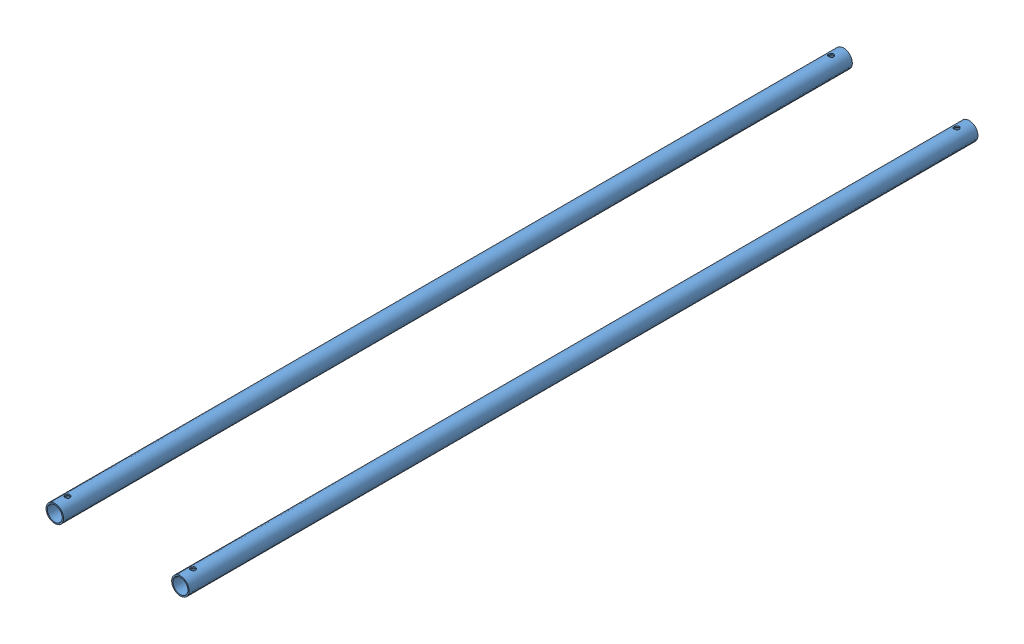
SolidWorks assembly BarreParalleles2, configuration Défaut. Lengths in mm.
Overall size (57 7 314).
2 component instances, 1 part files, 5 mates.
Components (placement in the parent):
- Pièce4_Tube-1: Pièce4_Tube [Défaut] at origin size (7 7 314)
- Pièce4_Tube-2: Pièce4_Tube [Défaut] at (50 0 0) size (7 7 314)
Mates (geometry in assembly coordinates):
- Parallèle1: parallel aligned: cylinder of Pièce4_Tube-1 through (0 10 5) axis (0 -1 0) radius 1; cylinder of Pièce4_Tube-2 through (50 10 6.4229) axis (0 -1 0) radius 1
- Parallèle2: parallel aligned: plane of Pièce4_Tube-2 through (50 0 0) normal (1 0 0); plane of assembly
- Coïncidente4: coincident aligned: plane of Pièce4_Tube-2 through (50 0 0) normal (0 1 0); plane of assembly
- Distance1: distance = 50 mm aligned: plane of assembly; plane of Pièce4_Tube-2 through (50 0 0) normal (1 0 0)
- Coïncidente6: coincident aligned: plane of Pièce4_Tube-2 through (50 0 0) normal (0 0 1); plane of assembly
